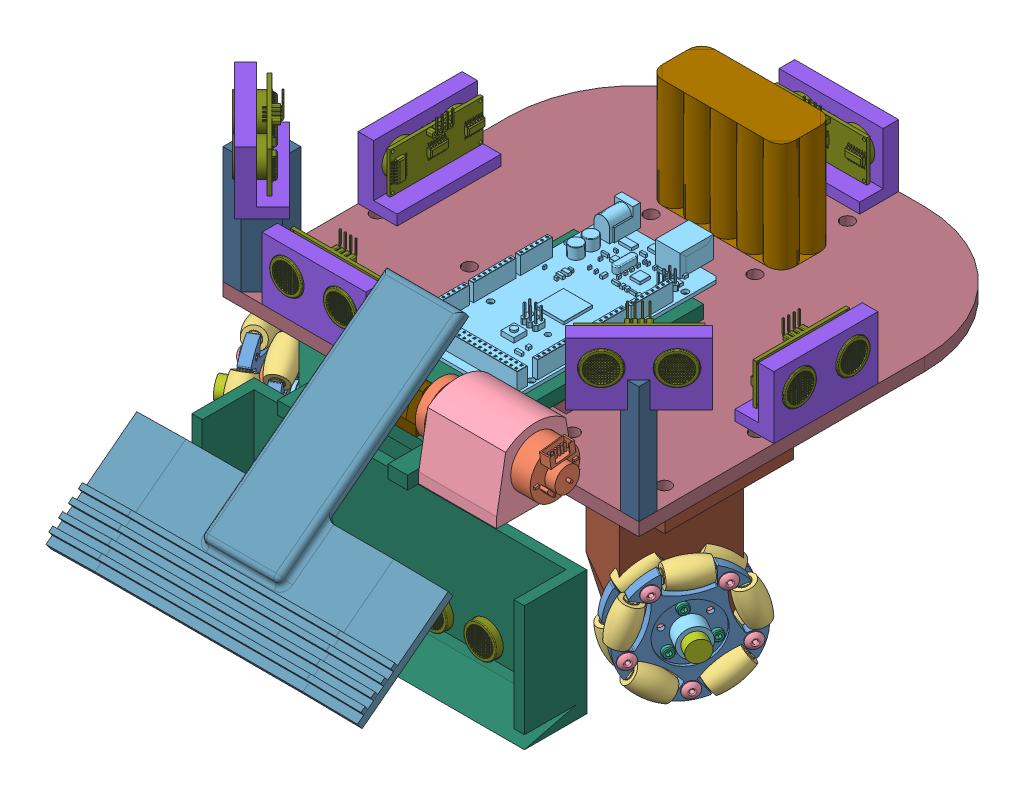
SolidWorks assembly Final_Assem_v3, configuration Default. Lengths in mm.
Overall size (266.21 184.22 334.42).
164 component instances, 32 part files, 108 mates.
Components (placement in the parent):
- WheelAsm-1: WheelAsm [Default] at (158.8212 -186.0529 155.5597) x (-0.148791 -0.954696 0.257713) z (-0.866025 0 -0.5) size (63.86 60.79 27.6)
  - WheelBase-2: WheelBase [Default] at (4.9023 2.731 55.3836) x (1 0 0) z (0 -1 0) size (56.86 5 54.96)
  - BasePlacer-1: BasePlacer [Default] at (4.9023 2.731 58.8836) x (1 0 0) z (0 -1 0) size (28 10 28)
  - RubberWheel-1: RubberWheel [Default] at (4.9023 26.7901 57.8836) x (1 0 0) z (0 -0.999594 -0.028494) size (19 12.5 12.5)
  - RubberWheel-2: RubberWheel [Default] at (-17.9792 10.1657 57.8836) x (0.309017 0.951057 0) z (0.95067 -0.308892 -0.028494) size (19 12.5 12.5)
  - RubberWheel-3: RubberWheel [Default] at (-9.2392 -16.7332 57.8836) x (-0.809017 0.587785 0) z (0.587547 0.808689 -0.028494) size (19 12.5 12.5)
  - RubberWheel-4: RubberWheel [Default] at (19.0439 -16.7332 57.8836) x (-0.809017 -0.587785 0) z (-0.587547 0.808689 -0.028494) size (19 12.5 12.5)
  - RubberWheel-5: RubberWheel [Default] at (27.7839 10.1657 57.8836) x (0.309017 -0.951057 0) z (-0.95067 -0.308892 -0.028494) size (19 12.5 12.5)
  - Rivet-1: Rivet [Default] at (4.9023 -21.269 54.8836) x (1 0 0) z (0 1 0) size (7.46 6.8 7.46)
  - Rivet-2: Rivet [Default] at (27.7277 -4.6854 54.8836) x (0.309017 0.951057 0) z (-0.951057 0.309017 0) size (7.46 6.8 7.46)
  - Rivet-3: Rivet [Default] at (19.0092 22.1474 54.8836) x (-0.809017 0.587785 0) z (-0.587785 -0.809017 0) size (7.46 6.8 7.46)
  - Rivet-4: Rivet [Default] at (-9.2045 22.1474 54.8836) x (-0.809017 -0.587785 0) z (0.587785 -0.809017 0) size (7.46 6.8 7.46)
  - Rivet-5: Rivet [Default] at (-17.923 -4.6854 54.8836) x (0.309017 -0.951057 0) z (0.951057 0.309017 0) size (7.46 6.8 7.46)
  - WheelBase-6: WheelBase [Default] at (4.9023 2.731 67.3836) x (-1 0 0) z (0 1 0) size (56.86 5 54.96)
  - RubberWheel-16: RubberWheel [Default] at (4.9023 -21.3281 69.8836) size (19 12.5 12.5)
  - RubberWheel-17: RubberWheel [Default] at (27.7839 -4.7037 69.8836) x (0.309017 0.951057 0) z (0 0 1) size (19 12.5 12.5)
  - RubberWheel-18: RubberWheel [Default] at (19.0439 22.1953 69.8836) x (-0.809017 0.587785 0) z (0 0 1) size (19 12.5 12.5)
  - RubberWheel-19: RubberWheel [Default] at (-9.2392 22.1953 69.8836) x (-0.809017 -0.587785 0) z (0 0 1) size (19 12.5 12.5)
  - RubberWheel-20: RubberWheel [Default] at (-17.9792 -4.7037 69.8836) x (0.309017 -0.951057 0) z (0 0 1) size (19 12.5 12.5)
  - Rivet-16: Rivet [Default] at (-9.2045 -16.6854 72.8836) x (-0.985624 0.168955 0) z (0.168955 0.985624 0) size (7.46 6.8 7.46)
  - Rivet-17: Rivet [Default] at (19.0092 -16.6854 72.8836) x (-0.46526 -0.885174 0) z (-0.885174 0.46526 0) size (7.46 6.8 7.46)
  - Rivet-18: Rivet [Default] at (27.7277 10.1474 72.8836) x (0.698077 -0.716022 0) z (-0.716022 -0.698077 0) size (7.46 6.8 7.46)
  - Rivet-19: Rivet [Default] at (4.9023 26.731 72.8836) x (0.896695 0.442648 0) z (0.442648 -0.896695 0) size (7.46 6.8 7.46)
  - Rivet-20: Rivet [Default] at (-17.923 10.1474 72.8836) x (-0.143889 0.989594 0) z (0.989594 0.143889 0) size (7.46 6.8 7.46)
  - ShaftConnector-1: ShaftConnector [Default] at (4.9023 2.731 48.8836) x (1 0 0) z (0 -1 0) size (14 27.6 14)
  - Part7^WheelAsm-1: Part7^WheelAsm [Default] at origin (virtual)
  - Part8^WheelAsm-1: Part8^WheelAsm [Default] at origin (virtual)
  - M3HexNut-1: M3HexNut [Default] at (13.9956 7.981 72.8836) x (1 0 0) z (0 0 -1) size (5 5 5)
  - M3HexNut-2: M3HexNut [Default] at (-4.1909 7.981 72.8836) x (-0.5 0.866025 0) z (0 0 -1) size (5 5 5)
  - M3HexNut-3: M3HexNut [Default] at (4.9023 -7.769 72.8836) x (-0.5 -0.866025 0) z (0 0 -1) size (5 5 5)
  - M3HexNut-4: M3HexNut [Default] at (4.9023 -7.769 54.8836) size (5 5 5)
  - M3HexNut-5: M3HexNut [Default] at (13.9956 7.981 54.8836) x (-0.5 0.866025 0) z (0 0 1) size (5 5 5)
  - M3HexNut-6: M3HexNut [Default] at (-4.1909 7.981 54.8836) x (-0.5 -0.866025 0) z (0 0 1) size (5 5 5)
- WheelAsm-2: WheelAsm [Default] at (14.2994 -187.213 -108.2515) x (-0.999988 0.004806 0) z (0 0 1) size (63.86 60.79 27.6)
  - WheelBase-2: WheelBase [Default] at (4.9023 2.731 55.3836) x (1 0 0) z (0 -1 0) size (56.86 5 54.96)
  - BasePlacer-1: BasePlacer [Default] at (4.9023 2.731 58.8836) x (1 0 0) z (0 -1 0) size (28 10 28)
  - RubberWheel-1: RubberWheel [Default] at (4.9023 26.7901 57.8836) x (1 0 0) z (0 -0.999594 -0.028494) size (19 12.5 12.5)
  - RubberWheel-2: RubberWheel [Default] at (-17.9792 10.1657 57.8836) x (0.309017 0.951057 0) z (0.95067 -0.308892 -0.028494) size (19 12.5 12.5)
  - RubberWheel-3: RubberWheel [Default] at (-9.2392 -16.7332 57.8836) x (-0.809017 0.587785 0) z (0.587547 0.808689 -0.028494) size (19 12.5 12.5)
  - RubberWheel-4: RubberWheel [Default] at (19.0439 -16.7332 57.8836) x (-0.809017 -0.587785 0) z (-0.587547 0.808689 -0.028494) size (19 12.5 12.5)
  - RubberWheel-5: RubberWheel [Default] at (27.7839 10.1657 57.8836) x (0.309017 -0.951057 0) z (-0.95067 -0.308892 -0.028494) size (19 12.5 12.5)
  - Rivet-1: Rivet [Default] at (4.9023 -21.269 54.8836) x (1 0 0) z (0 1 0) size (7.46 6.8 7.46)
  - Rivet-2: Rivet [Default] at (27.7277 -4.6854 54.8836) x (0.309017 0.951057 0) z (-0.951057 0.309017 0) size (7.46 6.8 7.46)
  - Rivet-3: Rivet [Default] at (19.0092 22.1474 54.8836) x (-0.809017 0.587785 0) z (-0.587785 -0.809017 0) size (7.46 6.8 7.46)
  - Rivet-4: Rivet [Default] at (-9.2045 22.1474 54.8836) x (-0.809017 -0.587785 0) z (0.587785 -0.809017 0) size (7.46 6.8 7.46)
  - Rivet-5: Rivet [Default] at (-17.923 -4.6854 54.8836) x (0.309017 -0.951057 0) z (0.951057 0.309017 0) size (7.46 6.8 7.46)
  - WheelBase-6: WheelBase [Default] at (4.9023 2.731 67.3836) x (-1 0 0) z (0 1 0) size (56.86 5 54.96)
  - RubberWheel-16: RubberWheel [Default] at (4.9023 -21.3281 69.8836) size (19 12.5 12.5)
  - RubberWheel-17: RubberWheel [Default] at (27.7839 -4.7037 69.8836) x (0.309017 0.951057 0) z (0 0 1) size (19 12.5 12.5)
  - RubberWheel-18: RubberWheel [Default] at (19.0439 22.1953 69.8836) x (-0.809017 0.587785 0) z (0 0 1) size (19 12.5 12.5)
  - RubberWheel-19: RubberWheel [Default] at (-9.2392 22.1953 69.8836) x (-0.809017 -0.587785 0) z (0 0 1) size (19 12.5 12.5)
  - RubberWheel-20: RubberWheel [Default] at (-17.9792 -4.7037 69.8836) x (0.309017 -0.951057 0) z (0 0 1) size (19 12.5 12.5)
  - Rivet-16: Rivet [Default] at (-9.2045 -16.6854 72.8836) x (-0.985624 0.168955 0) z (0.168955 0.985624 0) size (7.46 6.8 7.46)
  - Rivet-17: Rivet [Default] at (19.0092 -16.6854 72.8836) x (-0.46526 -0.885174 0) z (-0.885174 0.46526 0) size (7.46 6.8 7.46)
  - Rivet-18: Rivet [Default] at (27.7277 10.1474 72.8836) x (0.698077 -0.716022 0) z (-0.716022 -0.698077 0) size (7.46 6.8 7.46)
  - Rivet-19: Rivet [Default] at (4.9023 26.731 72.8836) x (0.896695 0.442648 0) z (0.442648 -0.896695 0) size (7.46 6.8 7.46)
  - Rivet-20: Rivet [Default] at (-17.923 10.1474 72.8836) x (-0.143889 0.989594 0) z (0.989594 0.143889 0) size (7.46 6.8 7.46)
  - ShaftConnector-1: ShaftConnector [Default] at (4.9023 2.731 48.8836) x (1 0 0) z (0 -1 0) size (14 27.6 14)
  - Part7^WheelAsm-1: Part7^WheelAsm [Default] at origin (virtual)
  - Part8^WheelAsm-1: Part8^WheelAsm [Default] at origin (virtual)
  - M3HexNut-1: M3HexNut [Default] at (13.9956 7.981 72.8836) x (1 0 0) z (0 0 -1) size (5 5 5)
  - M3HexNut-2: M3HexNut [Default] at (-4.1909 7.981 72.8836) x (-0.5 0.866025 0) z (0 0 -1) size (5 5 5)
  - M3HexNut-3: M3HexNut [Default] at (4.9023 -7.769 72.8836) x (-0.5 -0.866025 0) z (0 0 -1) size (5 5 5)
  - M3HexNut-4: M3HexNut [Default] at (4.9023 -7.769 54.8836) size (5 5 5)
  - M3HexNut-5: M3HexNut [Default] at (13.9956 7.981 54.8836) x (-0.5 0.866025 0) z (0 0 1) size (5 5 5)
  - M3HexNut-6: M3HexNut [Default] at (-4.1909 7.981 54.8836) x (-0.5 -0.866025 0) z (0 0 1) size (5 5 5)
- WheelAsm-3: WheelAsm [Default] at (-151.0302 -191.8955 160.5271) x (0.323209 0.762983 0.559814) z (0.866025 0 -0.5) size (63.86 60.79 27.6)
  - WheelBase-2: WheelBase [Default] at (4.9023 2.731 55.3836) x (1 0 0) z (0 -1 0) size (56.86 5 54.96)
  - BasePlacer-1: BasePlacer [Default] at (4.9023 2.731 58.8836) x (1 0 0) z (0 -1 0) size (28 10 28)
  - RubberWheel-1: RubberWheel [Default] at (4.9023 26.7901 57.8836) x (1 0 0) z (0 -0.999594 -0.028494) size (19 12.5 12.5)
  - RubberWheel-2: RubberWheel [Default] at (-17.9792 10.1657 57.8836) x (0.309017 0.951057 0) z (0.95067 -0.308892 -0.028494) size (19 12.5 12.5)
  - RubberWheel-3: RubberWheel [Default] at (-9.2392 -16.7332 57.8836) x (-0.809017 0.587785 0) z (0.587547 0.808689 -0.028494) size (19 12.5 12.5)
  - RubberWheel-4: RubberWheel [Default] at (19.0439 -16.7332 57.8836) x (-0.809017 -0.587785 0) z (-0.587547 0.808689 -0.028494) size (19 12.5 12.5)
  - RubberWheel-5: RubberWheel [Default] at (27.7839 10.1657 57.8836) x (0.309017 -0.951057 0) z (-0.95067 -0.308892 -0.028494) size (19 12.5 12.5)
  - Rivet-1: Rivet [Default] at (4.9023 -21.269 54.8836) x (1 0 0) z (0 1 0) size (7.46 6.8 7.46)
  - Rivet-2: Rivet [Default] at (27.7277 -4.6854 54.8836) x (0.309017 0.951057 0) z (-0.951057 0.309017 0) size (7.46 6.8 7.46)
  - Rivet-3: Rivet [Default] at (19.0092 22.1474 54.8836) x (-0.809017 0.587785 0) z (-0.587785 -0.809017 0) size (7.46 6.8 7.46)
  - Rivet-4: Rivet [Default] at (-9.2045 22.1474 54.8836) x (-0.809017 -0.587785 0) z (0.587785 -0.809017 0) size (7.46 6.8 7.46)
  - Rivet-5: Rivet [Default] at (-17.923 -4.6854 54.8836) x (0.309017 -0.951057 0) z (0.951057 0.309017 0) size (7.46 6.8 7.46)
  - WheelBase-6: WheelBase [Default] at (4.9023 2.731 67.3836) x (-1 0 0) z (0 1 0) size (56.86 5 54.96)
  - RubberWheel-16: RubberWheel [Default] at (4.9023 -21.3281 69.8836) size (19 12.5 12.5)
  - RubberWheel-17: RubberWheel [Default] at (27.7839 -4.7037 69.8836) x (0.309017 0.951057 0) z (0 0 1) size (19 12.5 12.5)
  - RubberWheel-18: RubberWheel [Default] at (19.0439 22.1953 69.8836) x (-0.809017 0.587785 0) z (0 0 1) size (19 12.5 12.5)
  - RubberWheel-19: RubberWheel [Default] at (-9.2392 22.1953 69.8836) x (-0.809017 -0.587785 0) z (0 0 1) size (19 12.5 12.5)
  - RubberWheel-20: RubberWheel [Default] at (-17.9792 -4.7037 69.8836) x (0.309017 -0.951057 0) z (0 0 1) size (19 12.5 12.5)
  - Rivet-16: Rivet [Default] at (-9.2045 -16.6854 72.8836) x (-0.985624 0.168955 0) z (0.168955 0.985624 0) size (7.46 6.8 7.46)
  - Rivet-17: Rivet [Default] at (19.0092 -16.6854 72.8836) x (-0.46526 -0.885174 0) z (-0.885174 0.46526 0) size (7.46 6.8 7.46)
  - Rivet-18: Rivet [Default] at (27.7277 10.1474 72.8836) x (0.698077 -0.716022 0) z (-0.716022 -0.698077 0) size (7.46 6.8 7.46)
  - Rivet-19: Rivet [Default] at (4.9023 26.731 72.8836) x (0.896695 0.442648 0) z (0.442648 -0.896695 0) size (7.46 6.8 7.46)
  - Rivet-20: Rivet [Default] at (-17.923 10.1474 72.8836) x (-0.143889 0.989594 0) z (0.989594 0.143889 0) size (7.46 6.8 7.46)
  - ShaftConnector-1: ShaftConnector [Default] at (4.9023 2.731 48.8836) x (1 0 0) z (0 -1 0) size (14 27.6 14)
  - Part7^WheelAsm-1: Part7^WheelAsm [Default] at origin (virtual)
  - Part8^WheelAsm-1: Part8^WheelAsm [Default] at origin (virtual)
  - M3HexNut-1: M3HexNut [Default] at (13.9956 7.981 72.8836) x (1 0 0) z (0 0 -1) size (5 5 5)
  - M3HexNut-2: M3HexNut [Default] at (-4.1909 7.981 72.8836) x (-0.5 0.866025 0) z (0 0 -1) size (5 5 5)
  - M3HexNut-3: M3HexNut [Default] at (4.9023 -7.769 72.8836) x (-0.5 -0.866025 0) z (0 0 -1) size (5 5 5)
  - M3HexNut-4: M3HexNut [Default] at (4.9023 -7.769 54.8836) size (5 5 5)
  - M3HexNut-5: M3HexNut [Default] at (13.9956 7.981 54.8836) x (-0.5 0.866025 0) z (0 0 1) size (5 5 5)
  - M3HexNut-6: M3HexNut [Default] at (-4.1909 7.981 54.8836) x (-0.5 -0.866025 0) z (0 0 1) size (5 5 5)
- DC Motor 12V-1: DC Motor 12V [Predeterminado] at (-59.1254 -189.9205 113.5312) x (0.5 0 0.866025) z (-0.866025 0 0.5) size (28.03 28 53.5)
  - Carcaça12V-1: Carcaça12V [Predeterminado] at (0 0 24.0663) size (28.03 28 32.04)
  - Bucha12V-1: Bucha12V [Predeterminado] at (0 0 26.0163) x (0.994754 0.102295 0) z (0 0 1) size (7 7 0.5)
  - Mancal12V-1: Mancal12V [Predeterminado] at (0 0 -2.9337) x (-1 0 0) z (0 0 -1) size (27.69 28 8)
  - Terminal12V-1: Terminal12V [Predeterminado] at (0 -11.5 -3.9337) x (1 0 0) z (0 1 0) size (2.9 10 0.4)
  - Terminal12V-2: Terminal12V [Predeterminado] at (0 11.5 -3.9337) x (1 0 0) z (0 1 0) size (2.9 10 0.4)
  - Eixo12V-1: Eixo12V [Predeterminado] at (0 0 39.5663) x (-0.33009 -0.943949 0) z (0 0 1) size (21 20.89 51)
  - Enrolamento12V-1: Enrolamento12V [Predeterminado] at (-5.1702 1.808 12.5663) x (0.33009 0.943949 0) z (0 0 1) size (10 3 20)
  - Enrolamento12V-2: Enrolamento12V [Predeterminado] at (1.0194 -5.3815 12.5663) x (-0.982529 -0.186108 0) z (0 0 1) size (10 3 20)
  - Enrolamento12V-3: Enrolamento12V [Predeterminado] at (4.1509 3.5736 12.5663) x (0.652439 -0.757841 0) z (0 0 1) size (10 3 20)
- DC Motor 12V-2: DC Motor 12V [Predeterminado] at (67.5444 -189.9205 107.5562) x (-0.212518 0.905176 0.368092) z (0.866025 0 0.5) size (28.03 28 53.5)
  - Carcaça12V-1: Carcaça12V [Predeterminado] at (0 0 24.0663) size (28.03 28 32.04)
  - Bucha12V-1: Bucha12V [Predeterminado] at (0 0 26.0163) x (0.994754 0.102295 0) z (0 0 1) size (7 7 0.5)
  - Mancal12V-1: Mancal12V [Predeterminado] at (0 0 -2.9337) x (-1 0 0) z (0 0 -1) size (27.69 28 8)
  - Terminal12V-1: Terminal12V [Predeterminado] at (0 -11.5 -3.9337) x (1 0 0) z (0 1 0) size (2.9 10 0.4)
  - Terminal12V-2: Terminal12V [Predeterminado] at (0 11.5 -3.9337) x (1 0 0) z (0 1 0) size (2.9 10 0.4)
  - Eixo12V-1: Eixo12V [Predeterminado] at (0 0 39.5663) x (-0.33009 -0.943949 0) z (0 0 1) size (21 20.89 51)
  - Enrolamento12V-1: Enrolamento12V [Predeterminado] at (-5.1702 1.808 12.5663) x (0.33009 0.943949 0) z (0 0 1) size (10 3 20)
  - Enrolamento12V-2: Enrolamento12V [Predeterminado] at (1.0194 -5.3815 12.5663) x (-0.982529 -0.186108 0) z (0 0 1) size (10 3 20)
  - Enrolamento12V-3: Enrolamento12V [Predeterminado] at (4.1509 3.5736 12.5663) x (0.652439 -0.757841 0) z (0 0 1) size (10 3 20)
- Acrylic Plate (square 12 inch) cut version-1: Acrylic Plate (square 12 inch) cut version [Default] at (9.384 -134.5485 57.0478) size (203.2 6.35 203.2)
- ScoopClawAssembly-1: ScoopClawAssembly [Default] at (-135.2234 -155.5644 109.464) size (171.3 138.74 218)
  - Scooper-1: Scooper [Default] at (144.6073 0.6103 138.0053) x (1 0 0) z (0 0.793599 0.608442) size (152.65 142.24 11.1)
  - Scooper_Base-1: Scooper_Base [Default] at (144.6073 -61.534 72.0438) size (162.56 95.25 144.78)
  - HC-SR04-UltrasonicSensor v7-2: HC-SR04-UltrasonicSensor v7 [Default] at (144.5683 -48.834 48.9638) x (-1 0 0) z (0 0 1) size (45.45 26.2 17.79)
  - Hinge_Joint-1: Hinge_Joint [Default] at (126.8273 46.416 67.8239) x (0 0.774266 0.63286) z (1 0 0) size (8.89 8.89 40.64)
  - Hinge_Part1-1: Hinge_Part1 [Default] at (144.6073 33.716 67.8239) size (35.56 18.62 12.7)
  - Hinge_Part2-1: Hinge_Part2 [Default] at (144.6073 54.4789 74.0056) x (1 0 0) z (0 0.608442 -0.793599) size (25.4 16.08 12.7)
  - 6V Motor Spin-1: 6V Motor Spin [Default] at (231.6559 14.0419 25.1949) x (-0.072098 -0.103157 0.992049) z (-0.996718 0.044149 -0.067847) size (29.63 28.32 78.39)
    - Motor no spinny boi-1: Motor no spinny boi [Default] at (39.6165 36.3483 7.7453) x (0.997226 -0.015871 -0.072721) z (0.072098 -0.036799 0.996718) size (24.4 25.49 66.9)
    - Motor spinny boi-1: Motor spinny boi [Default] at (39.6165 36.3483 7.7453) x (0.547957 0.836461 -0.008754) z (0.072098 -0.036799 0.996718) size (3.95 3.95 13.05)
  - Motor Support-1: Motor Support [Default] at (195.4073 27.366 67.8239) size (38.1 54.53 38.1)
- ArduinoMega-1: ArduinoMega [Default] at (9.3459 -119.6895 95.1478) x (0 0 -1) z (0 -1 0) size (107.95 53.42 12.95)
- 12V Motor Support -Right-2: 12V Motor Support -Right [Default] at (-60.72 -189.9205 114.4518) x (0.866025 0 -0.5) z (0.5 0 0.866025) size (86.05 76.69 86.05)
- OmniWheel_Connection Piece-2: OmniWheel_Connection Piece [Default] at (90.257 -189.9205 120.6693) x (-0.490726 0.19171 0.849962) z (0.866025 0 0.5) size (10.16 10.16 33.02)
- OmniWheel_Connection Piece-3: OmniWheel_Connection Piece [Default] at (-81.8727 -189.9205 126.6643) x (0.5 0 0.866025) z (-0.866025 0 0.5) size (10.16 10.16 33.02)
- HC-SR04-UltrasonicSensor v7-1: HC-SR04-UltrasonicSensor v7 [Default] at (-40.996 -204.3985 158.4278) x (-1 0 0) z (0 0 1) size (45.45 26.2 17.79)
- HC-SR04-UltrasonicSensor v7-2: HC-SR04-UltrasonicSensor v7 [Default] at (59.764 -204.3985 158.4278) x (-1 0 0) z (0 0 1) size (45.45 26.2 17.79)
- US_Support-2: US_Support [Default] at (103.364 -123.1185 67.2078) x (0 0 -1) z (1 0 0) size (50.8 30.48 19.05)
- US_Support-3: US_Support [Default] at (-84.596 -123.1185 67.2078) x (0 0 1) z (-1 0 0) size (50.8 30.48 19.05)
- BatteryRemodeled-2: BatteryRemodeled [Default] at (34.784 -76.1031 -0.1022) x (-1 0 0) z (0 0 1) size (64.52 53.39 25.65)
- US_Support-4: US_Support [Default] at (9.384 -123.1185 -36.9322) x (-1 0 0) z (0 0 -1) size (50.8 30.48 19.05)
- US_Support-5: US_Support [Default] at (-47.766 -123.1185 151.0278) size (50.8 30.48 19.05)
- HC-SR04-UltrasonicSensor v7-3: HC-SR04-UltrasonicSensor v7 [Default] at (98.064 -110.4185 67.1688) x (0 0 1) z (1 0 0) size (45.45 26.2 17.79)
- HC-SR04-UltrasonicSensor v7-4: HC-SR04-UltrasonicSensor v7 [Default] at (9.345 -110.4185 -31.6322) x (1 0 0) z (0 0 -1) size (45.45 26.2 17.79)
- HC-SR04-UltrasonicSensor v7-5: HC-SR04-UltrasonicSensor v7 [Default] at (-79.296 -110.4185 67.1688) x (0 0 -1) z (-1 0 0) size (45.45 26.2 17.79)
- corner_support-1: corner_support [Default] at (-82.691 -128.1985 149.1228) size (19.05 57.15 19.05)
- US_Support-6: US_Support [Default] at (-84.1338 -78.6685 150.386) x (0.707107 0 0.707107) z (-0.707107 0 0.707107) size (50.8 30.48 19.05)
- HC-SR04-UltrasonicSensor v7-6: HC-SR04-UltrasonicSensor v7 [Default] at (-80.3586 -65.9685 146.6659) x (-0.707107 0 -0.707107) z (-0.707107 0 0.707107) size (45.45 26.2 17.79)
- HC-SR04-UltrasonicSensor v7-7: HC-SR04-UltrasonicSensor v7 [Default] at (-47.805 -110.4185 145.7278) x (-1 0 0) z (0 0 1) size (45.45 26.2 17.79)
- corner_support-2: corner_support [Default] at (101.459 -128.1985 149.1228) x (0 0 -1) z (1 0 0) size (19.05 57.15 19.05)
- US_Support-7: US_Support [Default] at (102.9017 -78.6685 150.386) x (0.707107 0 -0.707107) z (0.707107 0 0.707107) size (50.8 30.48 19.05)
- HC-SR04-UltrasonicSensor v7-8: HC-SR04-UltrasonicSensor v7 [Default] at (99.1265 -65.9685 146.6659) x (-0.707107 0 0.707107) z (0.707107 0 0.707107) size (45.45 26.2 17.79)
- 12V Motor Support - Left-1: 12V Motor Support - Left [Default] at (79.488 -189.9205 114.4518) x (0.866025 0 0.5) z (-0.5 0 0.866025) size (86.05 76.69 86.05)
- DC Motor 12V-3: DC Motor 12V [Predeterminado] at (9.384 -189.9205 -5.2016) x (-0.923728 -0.383049 0) z (0 0 -1) size (28.03 28 53.5)
  - Carcaça12V-1: Carcaça12V [Predeterminado] at (0 0 24.0663) size (28.03 28 32.04)
  - Bucha12V-1: Bucha12V [Predeterminado] at (0 0 26.0163) x (0.994754 0.102295 0) z (0 0 1) size (7 7 0.5)
  - Mancal12V-1: Mancal12V [Predeterminado] at (0 0 -2.9337) x (-1 0 0) z (0 0 -1) size (27.69 28 8)
  - Terminal12V-1: Terminal12V [Predeterminado] at (0 -11.5 -3.9337) x (1 0 0) z (0 1 0) size (2.9 10 0.4)
  - Terminal12V-2: Terminal12V [Predeterminado] at (0 11.5 -3.9337) x (1 0 0) z (0 1 0) size (2.9 10 0.4)
  - Eixo12V-1: Eixo12V [Predeterminado] at (0 0 39.5663) x (-0.33009 -0.943949 0) z (0 0 1) size (21 20.89 51)
  - Enrolamento12V-1: Enrolamento12V [Predeterminado] at (-5.1702 1.808 12.5663) x (0.33009 0.943949 0) z (0 0 1) size (10 3 20)
  - Enrolamento12V-2: Enrolamento12V [Predeterminado] at (1.0194 -5.3815 12.5663) x (-0.982529 -0.186108 0) z (0 0 1) size (10 3 20)
  - Enrolamento12V-3: Enrolamento12V [Predeterminado] at (4.1509 3.5736 12.5663) x (0.652439 -0.757841 0) z (0 0 1) size (10 3 20)
- 12V Motor Support - Rear-1: 12V Motor Support - Rear [Default] at (9.384 -189.9205 -7.0429) x (0 0 -1) z (1 0 0) size (62.99 76.31 63.5)
Mates (geometry in assembly coordinates):
- Coincident3: coincident: plane of Acrylic Plate (square 12 inch) cut version-1 through (9.384 -128.1985 57.0478) normal (0 1 0); plane of ScoopClawAssembly-1/Scooper_Base-1 through (9.384 -128.1985 181.5078) normal (0 -1 0)
- Coincident4: coincident: plane of Acrylic Plate (square 12 inch) cut version-1 through (-92.216 -128.1985 158.6478) normal (0 0 1); plane of ScoopClawAssembly-1/Scooper_Base-1 through (9.384 -217.0985 158.6478) normal (0 0 -1)
- Distance4: distance = 0.508 mm: plane of ScoopClawAssembly-1/Scooper_Base-1 through (9.384 -121.8485 181.5078) normal (0 1 0); plane of ArduinoMega-1 through (-17.3622 -121.3405 44.3478) normal (0 -1 0)
- Distance6: distance = 12.7 mm: plane of ArduinoMega-1 through (36.054 -121.3405 44.3478) normal (0 0 -1); plane of ScoopClawAssembly-1/Scooper_Base-1 through (41.134 -121.8485 57.0478) normal (0 0 -1)
- Distance7: distance = 5.08 mm: plane of ArduinoMega-1 through (36.054 -121.3405 145.9478) normal (1 0 0); plane of ScoopClawAssembly-1/Scooper_Base-1 through (41.134 -166.2985 158.6478) normal (1 0 0)
- Coincident23: coincident: plane of Acrylic Plate (square 12 inch) cut version-1 through (9.384 -134.5485 57.0478) normal (0 -1 0); plane of ? through (146.5657 -134.5485 103.1381) normal (0 1 0)
- Coincident29: coincident: plane of Acrylic Plate (square 12 inch) cut version-1 through (9.384 -134.5485 57.0478) normal (0 -1 0); plane of 12V Motor Support -Right-2 through (-60.72 -134.5485 114.4518) normal (0 1 0)
- Concentric1: concentric: cylinder of DC Motor 12V-1/Carcaça12V-1 through (-54.8527 -189.9205 111.0643) axis (-0.866025 0 0.5) radius 14; cylinder of 12V Motor Support -Right-2 through (-151.4579 -189.9205 166.8393) axis (0.866025 0 -0.5) radius 17.145
- Coincident31: coincident: plane of DC Motor 12V-1/Carcaça12V-1 through (-79.9675 -189.9205 125.5643) normal (-0.866025 0 0.5); plane of 12V Motor Support -Right-2 through (-68.855 -139.6285 144.8117) normal (-0.866025 0 0.5)
- Coincident32: coincident: plane of DC Motor 12V-2/Carcaça12V-1; plane of ? through (144.59 -139.6285 128.1032) normal (0.707107 0 0.707107)
- Concentric2: concentric: cylinder of DC Motor 12V-2/Carcaça12V-1 through (137.5543 -189.9205 94.1267) axis (0.707107 0 0.707107) radius 14; cylinder of ? through (68.2578 -189.9205 24.8302) axis (0.707107 0 0.707107) radius 13.9872
- Concentric4: concentric: circle of WheelAsm-1/ShaftConnector-1; circle of DC Motor 12V-2/Eixo12V-1
- Coincident36: coincident: plane of WheelAsm-1/ShaftConnector-1 through (90.5514 -189.9205 120.8393) normal (-0.866025 0 -0.5); plane of DC Motor 12V-2/Carcaça12V-1 through (90.5514 -189.9205 120.8393) normal (0.866025 0 0.5)
- Concentric8: concentric: circle of WheelAsm-1/ShaftConnector-1; circle of OmniWheel_Connection Piece-2
- Coincident39: coincident: plane of WheelAsm-1/ShaftConnector-1 through (114.4537 -189.9205 134.6393) normal (0.866025 0 0.5); plane of OmniWheel_Connection Piece-2 through (114.4537 -189.9205 134.6393) normal (-0.866025 0 -0.5)
- Distance9: distance = 69.85 mm: plane of ScoopClawAssembly-1/Scooper_Base-1 through (-22.366 -128.1985 158.6478) normal (-1 0 0); plane of Acrylic Plate (square 12 inch) cut version-1 through (-92.216 -128.1985 158.6478) normal (-1 0 0)
- Concentric9: concentric: circle of WheelAsm-3/ShaftConnector-1; circle of DC Motor 12V-1/Eixo12V-1
- Coincident42: coincident: plane of WheelAsm-3/ShaftConnector-1 through (-106.0695 -189.9205 140.6343) normal (-0.866025 0 0.5); plane of OmniWheel_Connection Piece-3 through (-106.0695 -189.9205 140.6343) normal (0.866025 0 -0.5)
- Concentric10: concentric: circle of WheelAsm-3/ShaftConnector-1; circle of OmniWheel_Connection Piece-3
- Coincident43: coincident: plane of DC Motor 12V-1/Bucha12V-1 through (-81.8727 -189.9205 126.6643) normal (-0.866025 0 0.5); plane of OmniWheel_Connection Piece-3 through (-81.8727 -189.9205 126.6643) normal (0.866025 0 -0.5)
- Coincident45: coincident: plane of Acrylic Plate (square 12 inch) cut version-1 through (9.384 -134.5485 57.0478) normal (0 -1 0); plane of ? through (9.384 -134.5485 2.4378) normal (0 1 0)
- Concentric13: concentric: circle of WheelAsm-2/ShaftConnector-1; circle of ?
- Concentric14: concentric: circle of WheelAsm-2/ShaftConnector-1; circle of ?
- Coincident52: coincident: plane of WheelAsm-2/ShaftConnector-1 through (9.384 -189.9205 -53.3622) normal (0 0 -1); plane of ? through (9.384 -189.9205 -53.3622) normal (0 0 1)
- Distance13: distance = 18.034 mm: plane of ? through (41.134 -134.5485 -26.5182) normal (0 0 -1); plane of Acrylic Plate (square 12 inch) cut version-1 through (-92.216 -128.1985 -44.5522) normal (0 0 -1)
- Distance15: distance = 69.85 mm: plane of ? through (41.134 -134.5485 -26.5182) normal (1 0 0); plane of Acrylic Plate (square 12 inch) cut version-1 through (110.984 -128.1985 158.6478) normal (1 0 0)
- Coincident73: coincident: plane of ScoopClawAssembly-1/Scooper_Base-1 through (9.384 -121.8485 181.5078) normal (0 1 0); plane of ? through (38.594 -121.8485 59.5878) normal (0 -1 0)
- Coincident74: coincident: plane of ScoopClawAssembly-1/Scooper_Base-1 through (41.134 -121.8485 57.0478) normal (0 0 -1); plane of ? through (41.134 -121.8485 57.0478) normal (0 0 -1)
- Coincident75: coincident: plane of ScoopClawAssembly-1/Scooper_Base-1 through (41.134 -166.2985 158.6478) normal (1 0 0); plane of ? through (41.134 -121.8485 62.1278) normal (1 0 0)
- Coincident76: coincident: plane of ScoopClawAssembly-1/Scooper_Base-1 through (41.134 -121.8485 57.0478) normal (0 0 -1); plane of ? through (-22.366 -83.7485 57.0478) normal (0 0 -1)
- Coincident77: coincident: plane of ScoopClawAssembly-1/Scooper_Base-1 through (9.384 -121.8485 181.5078) normal (0 1 0); plane of ? through (-19.826 -121.8485 59.5878) normal (0 -1 0)
- Coincident78: coincident: plane of ScoopClawAssembly-1/Scooper_Base-1 through (-22.366 -128.1985 158.6478) normal (-1 0 0); plane of ? through (-22.366 -83.7485 62.1278) normal (-1 0 0)
- Coincident79: coincident: plane of ScoopClawAssembly-1/Scooper_Base-1 through (9.384 -121.8485 181.5078) normal (0 1 0); plane of ? through (38.594 -121.8485 105.3042) normal (0 -1 0)
- Coincident80: coincident: plane of ? through (41.134 -121.8485 62.1278) normal (1 0 0); plane of ? through (41.134 -121.8485 107.8442) normal (1 0 0)
- Distance21: distance = 55.4736 mm: plane of ? through (41.134 -121.8485 102.7642) normal (0 0 -1); plane of ScoopClawAssembly-1/Motor Support-1 through (41.134 -123.1185 158.2378) normal (0 0 -1)
- Coincident82: coincident: plane of ? through (-22.366 -83.7485 102.7642) normal (0 0 -1); plane of ? through (41.134 -121.8485 102.7642) normal (0 0 -1)
- Coincident83: coincident: plane of ScoopClawAssembly-1/Scooper_Base-1 through (9.384 -121.8485 181.5078) normal (0 1 0); plane of ? through (-19.826 -121.8485 105.3042) normal (0 -1 0)
- Coincident84: coincident: plane of ScoopClawAssembly-1/Scooper_Base-1 through (-22.366 -128.1985 158.6478) normal (-1 0 0); plane of ? through (-22.366 -83.7485 107.8442) normal (-1 0 0)
- Coincident85: coincident: plane of ? through (38.594 -83.7485 59.5878) normal (0 1 0); plane of ? through (9.384 -83.7485 82.4478) normal (0 -1 0)
- Coincident88: coincident: plane of ? through (-22.366 -83.7485 57.0478) normal (0 0 -1); plane of ? through (60.184 -77.3985 57.0478) normal (0 0 -1)
- Distance22: distance = 19.05 mm: plane of ? through (-41.416 -77.3985 57.0478) normal (-1 0 0); plane of ? through (-22.366 -83.7485 62.1278) normal (-1 0 0)
- Coincident91: coincident: plane of ScoopClawAssembly-1/Scooper_Base-1 through (9.384 -217.0985 163.7278) normal (0 0 -1); plane of HC-SR04-UltrasonicSensor v7-2 through (59.764 -211.7841 163.7278) normal (0 0 1)
- Parallel9: parallel: plane of ScoopClawAssembly-1/Scooper_Base-1 through (9.384 -217.0985 181.5078) normal (0 -1 0); plane of HC-SR04-UltrasonicSensor v7-2 through (37.039 -214.3985 158.4278) normal (0 -1 0)
- Parallel10: parallel: plane of ScoopClawAssembly-1/Scooper_Base-1 through (9.384 -217.0985 181.5078) normal (0 -1 0); plane of HC-SR04-UltrasonicSensor v7-1 through (-63.721 -214.3985 158.4278) normal (0 -1 0)
- Coincident94: coincident: plane of ScoopClawAssembly-1/Scooper_Base-1 through (9.384 -217.0985 163.7278) normal (0 0 -1); plane of HC-SR04-UltrasonicSensor v7-1 through (-40.996 -211.7841 163.7278) normal (0 0 1)
- Coincident95: coincident: plane of Acrylic Plate (square 12 inch) cut version-1 through (110.984 -128.1985 158.6478) normal (1 0 0); plane of US_Support-2 through (110.984 -123.1185 67.2078) normal (1 0 0)
- Coincident96: coincident: plane of Acrylic Plate (square 12 inch) cut version-1 through (9.384 -128.1985 57.0478) normal (0 1 0); plane of US_Support-2 through (103.364 -128.1985 67.2078) normal (0 -1 0)
- Distance23: distance = 86.36 mm: plane of US_Support-2 through (110.984 -123.1185 41.8078) normal (0 0 -1); plane of Acrylic Plate (square 12 inch) cut version-1 through (-92.216 -128.1985 -44.5522) normal (0 0 -1)
- Coincident98: coincident: plane of US_Support-2 through (110.984 -123.1185 92.6078) normal (0 0 1); plane of US_Support-3 through (-92.216 -123.1185 92.6078) normal (0 0 1)
- Coincident99: coincident: plane of Acrylic Plate (square 12 inch) cut version-1 through (9.384 -128.1985 57.0478) normal (0 1 0); plane of US_Support-3 through (-84.596 -128.1985 67.2078) normal (0 -1 0)
- Coincident100: coincident: plane of Acrylic Plate (square 12 inch) cut version-1 through (-92.216 -128.1985 158.6478) normal (-1 0 0); plane of US_Support-3 through (-92.216 -123.1185 67.2078) normal (-1 0 0)
- Coincident101: coincident: plane of Acrylic Plate (square 12 inch) cut version-1 through (9.384 -128.1985 57.0478) normal (0 1 0); plane of BatteryRemodeled-2 through (34.784 -128.1985 -0.1022) normal (0 -1 0)
- Distance24: distance = 38.1 mm: line of BatteryRemodeled-2 through (-4.078 -128.1731 -6.4522) axis (1 0 0); line of Acrylic Plate (square 12 inch) cut version-1 through (47.484 -128.1985 -44.5522) axis (-1 0 0)
- Distance25: distance = 69.85 mm: line of BatteryRemodeled-2 through (41.134 -128.1731 -0.1022) axis (0 0 1); line of Acrylic Plate (square 12 inch) cut version-1 through (110.984 -128.1985 158.6478) axis (0 0 -1)
- Coincident106: coincident: plane of Acrylic Plate (square 12 inch) cut version-1 through (-92.216 -128.1985 -44.5522) normal (0 0 -1); plane of US_Support-4 through (9.384 -123.1185 -44.5522) normal (0 0 -1)
- Coincident107: coincident: plane of Acrylic Plate (square 12 inch) cut version-1 through (9.384 -128.1985 57.0478) normal (0 1 0); plane of US_Support-4 through (9.384 -128.1985 -36.9322) normal (0 -1 0)
- Distance26: distance = 76.2 mm: plane of US_Support-4 through (-16.016 -123.1185 -44.5522) normal (-1 0 0); plane of Acrylic Plate (square 12 inch) cut version-1 through (-92.216 -128.1985 158.6478) normal (-1 0 0)
- Coincident109: coincident: plane of Acrylic Plate (square 12 inch) cut version-1 through (9.384 -128.1985 57.0478) normal (0 1 0); plane of US_Support-5 through (-47.766 -128.1985 151.0278) normal (0 -1 0)
- Distance27: distance = 19.05 mm: plane of US_Support-5 through (-73.166 -123.1185 158.6478) normal (-1 0 0); plane of Acrylic Plate (square 12 inch) cut version-1 through (-92.216 -128.1985 158.6478) normal (-1 0 0)
- Coincident111: coincident: plane of Acrylic Plate (square 12 inch) cut version-1 through (-92.216 -128.1985 158.6478) normal (0 0 1); plane of US_Support-5 through (-47.766 -123.1185 158.6478) normal (0 0 1)
- Concentric20: concentric: cylinder of HC-SR04-UltrasonicSensor v7-5 through (-80.896 -110.4185 80.2888) axis (-1 0 0) radius 8; cylinder of US_Support-3 through (-92.216 -110.4185 80.2888) axis (1 0 0) radius 8.2697
- Parallel16: parallel: plane of US_Support-3 through (-92.216 -97.7185 41.8078) normal (0 1 0); plane of HC-SR04-UltrasonicSensor v7-5 through (-79.296 -100.4185 89.8938) normal (0 1 0)
- Coincident114: coincident: plane of US_Support-3 through (-84.596 -123.1185 67.2078) normal (1 0 0); plane of HC-SR04-UltrasonicSensor v7-5 through (-84.596 -117.8041 67.1688) normal (-1 0 0)
- Concentric21: concentric: cylinder of US_Support-2 through (110.984 -110.4185 80.2888) axis (-1 0 0) radius 8.2697; cylinder of HC-SR04-UltrasonicSensor v7-3 through (99.664 -110.4185 80.2888) axis (1 0 0) radius 8
- Parallel17: parallel: plane of US_Support-2 through (103.364 -123.1185 67.2078) normal (0 1 0); plane of HC-SR04-UltrasonicSensor v7-3 through (98.064 -120.4185 89.8938) normal (0 -1 0)
- Coincident116: coincident: plane of US_Support-2 through (103.364 -123.1185 67.2078) normal (-1 0 0); plane of HC-SR04-UltrasonicSensor v7-3 through (103.364 -117.8041 67.1688) normal (1 0 0)
- Concentric23: concentric: cylinder of US_Support-4 through (22.465 -110.4185 -44.5522) axis (0 0 1) radius 8.2697; cylinder of HC-SR04-UltrasonicSensor v7-4 through (22.465 -110.4185 -33.2322) axis (0 0 -1) radius 8
- Parallel18: parallel: plane of US_Support-4 through (9.384 -123.1185 -36.9322) normal (0 1 0); plane of HC-SR04-UltrasonicSensor v7-4 through (32.07 -120.4185 -31.6322) normal (0 -1 0)
- Coincident118: coincident: plane of US_Support-4 through (9.384 -123.1185 -36.9322) normal (0 0 1); plane of HC-SR04-UltrasonicSensor v7-4 through (9.345 -117.8041 -36.9322) normal (0 0 -1)
- Coincident119: coincident: plane of Acrylic Plate (square 12 inch) cut version-1 through (-92.216 -128.1985 158.6478) normal (-1 0 0); plane of corner_support-1 through (-92.216 -83.7485 158.6478) normal (-1 0 0)
- Coincident120: coincident: plane of Acrylic Plate (square 12 inch) cut version-1 through (9.384 -128.1985 57.0478) normal (0 1 0); plane of corner_support-1 through (-82.691 -128.1985 149.1228) normal (0 -1 0)
- Coincident121: coincident: plane of Acrylic Plate (square 12 inch) cut version-1 through (-92.216 -128.1985 158.6478) normal (0 0 1); plane of corner_support-1 through (-92.216 -83.7485 158.6478) normal (0 0 1)
- Coincident135: coincident: plane of corner_support-1 through (-86.6483 -71.0485 158.6478) normal (0.707107 0 -0.707107); plane of US_Support-6 through (-89.522 -78.6685 155.7741) normal (-0.707107 0 0.707107)
- Concentric24: concentric: cylinder of US_Support-6 through (-98.7716 -65.9685 146.5245) axis (0.707107 0 -0.707107) radius 8.2697; cylinder of HC-SR04-UltrasonicSensor v7-6 through (-90.7672 -65.9685 138.52) axis (-0.707107 0 0.707107) radius 8
- Parallel23: parallel: plane of US_Support-6 through (-84.1338 -78.6685 150.386) normal (0 1 0); plane of HC-SR04-UltrasonicSensor v7-6 through (-96.4276 -75.9685 130.5969) normal (0 -1 0)
- Coincident138: coincident: plane of US_Support-6 through (-84.1338 -78.6685 150.386) normal (0.707107 0 -0.707107); plane of HC-SR04-UltrasonicSensor v7-6 through (-84.1062 -73.3541 150.4136) normal (-0.707107 0 0.707107)
- Concentric25: concentric: cylinder of US_Support-5 through (-34.685 -110.4185 158.6478) axis (0 0 -1) radius 8.2697; cylinder of HC-SR04-UltrasonicSensor v7-7 through (-34.685 -110.4185 147.3278) axis (0 0 1) radius 8
- Parallel24: parallel: plane of US_Support-5 through (-73.166 -97.7185 158.6478) normal (0 1 0); plane of HC-SR04-UltrasonicSensor v7-7 through (-25.08 -100.4185 145.7278) normal (0 1 0)
- Coincident140: coincident: plane of US_Support-5 through (-47.766 -123.1185 151.0278) normal (0 0 -1); plane of HC-SR04-UltrasonicSensor v7-7 through (-47.805 -117.8041 151.0278) normal (0 0 1)
- Coincident142: coincident: plane of Acrylic Plate (square 12 inch) cut version-1 through (110.984 -128.1985 158.6478) normal (1 0 0); plane of corner_support-2 through (110.984 -83.7485 158.6478) normal (1 0 0)
- Coincident143: coincident: plane of Acrylic Plate (square 12 inch) cut version-1 through (9.384 -128.1985 57.0478) normal (0 1 0); plane of corner_support-2 through (101.459 -128.1985 149.1228) normal (0 -1 0)
- Coincident144: coincident: plane of Acrylic Plate (square 12 inch) cut version-1 through (-92.216 -128.1985 158.6478) normal (0 0 1); plane of corner_support-2 through (110.984 -83.7485 158.6478) normal (0 0 1)
- Coincident145: coincident: plane of corner_support-1 through (-82.691 -83.7485 149.1228) normal (0 1 0); plane of US_Support-6 through (-84.1338 -83.7485 150.386) normal (0 -1 0)
- Distance35: distance = 21.59 mm: line of corner_support-1 through (-92.216 -71.0485 153.0801) axis (0 -1 0); line of US_Support-6 through (-107.4825 -53.2685 137.8136) axis (0 -1 0)
- Coincident148: coincident: plane of corner_support-2 through (101.459 -83.7485 149.1228) normal (0 1 0); plane of US_Support-7 through (102.9017 -83.7485 150.386) normal (0 -1 0)
- Coincident150: coincident: plane of corner_support-2 through (110.984 -71.0485 153.0801) normal (-0.707107 0 -0.707107); plane of US_Support-7 through (108.2899 -78.6685 155.7741) normal (0.707107 0 0.707107)
- Distance36: distance = 21.59 mm: line of US_Support-7 through (126.2504 -83.7485 137.8136) axis (0 1 0); line of corner_support-2 through (110.984 -71.0485 153.0801) axis (0 -1 0)
- Concentric26: concentric: cylinder of US_Support-7 through (117.5395 -65.9685 146.5245) axis (-0.707107 0 -0.707107) radius 8.2697; cylinder of HC-SR04-UltrasonicSensor v7-8 through (109.5351 -65.9685 138.52) axis (0.707107 0 0.707107) radius 8
- Parallel25: parallel: plane of US_Support-7 through (102.9017 -78.6685 150.386) normal (0 1 0); plane of HC-SR04-UltrasonicSensor v7-8 through (83.0575 -75.9685 162.7349) normal (0 -1 0)
- Coincident153: coincident: plane of US_Support-7 through (102.9017 -78.6685 150.386) normal (-0.707107 0 -0.707107); plane of HC-SR04-UltrasonicSensor v7-8 through (102.8742 -73.3541 150.4136) normal (0.707107 0 0.707107)
- Concentric27: concentric: cylinder of ScoopClawAssembly-1/Scooper_Base-1 through (72.884 -204.3985 171.3478) axis (0 0 -1) radius 8.2697; cylinder of HC-SR04-UltrasonicSensor v7-2 through (72.884 -204.3985 160.0278) axis (0 0 1) radius 8
- Concentric28: concentric: cylinder of ScoopClawAssembly-1/Scooper_Base-1 through (-54.116 -204.3985 171.3478) axis (0 0 -1) radius 8.2697; cylinder of HC-SR04-UltrasonicSensor v7-1 through (-54.116 -204.3985 160.0278) axis (0 0 1) radius 8
- Coincident168: coincident: plane of Acrylic Plate (square 12 inch) cut version-1 through (9.384 -134.5485 57.0478) normal (0 -1 0); plane of 12V Motor Support -Right-2 through (-60.72 -134.5485 114.4518) normal (0 1 0)
- Coincident169: coincident: plane of Acrylic Plate (square 12 inch) cut version-1 through (9.384 -134.5485 57.0478) normal (0 -1 0); plane of 12V Motor Support -Right-2 through (-60.72 -134.5485 114.4518) normal (0 1 0)
- Coincident170: coincident: plane of Acrylic Plate (square 12 inch) cut version-1 through (-92.216 -128.1985 158.6478) normal (-1 0 0); plane of 12V Motor Support -Right-2 through (-92.216 -134.5485 145.9478) normal (-1 0 0)
- Distance37: distance = 12.7 mm: plane of 12V Motor Support -Right-2 through (-29.224 -134.5485 145.9478) normal (0 0 1); plane of Acrylic Plate (square 12 inch) cut version-1 through (-92.216 -128.1985 158.6478) normal (0 0 1)
- Coincident180: coincident: plane of Acrylic Plate (square 12 inch) cut version-1 through (9.384 -134.5485 57.0478) normal (0 -1 0); plane of 12V Motor Support - Left-1 through (79.488 -134.5485 114.4518) normal (0 1 0)
- Coincident184: coincident: plane of Acrylic Plate (square 12 inch) cut version-1 through (110.984 -128.1985 158.6478) normal (1 0 0); plane of 12V Motor Support - Left-1 through (110.984 -134.5485 82.9558) normal (1 0 0)
- Distance38: distance = 12.7 mm: plane of Acrylic Plate (square 12 inch) cut version-1 through (-92.216 -128.1985 158.6478) normal (0 0 1); plane of 12V Motor Support - Left-1 through (110.984 -134.5485 145.9478) normal (0 0 1)
- Concentric29: concentric: cylinder of DC Motor 12V-2/Carcaça12V-1 through (63.2716 -189.9205 105.0893) axis (0.866025 0 0.5) radius 14; cylinder of 12V Motor Support - Left-1 through (-11.2499 -189.9205 62.0643) axis (0.866025 0 0.5) radius 17.145
- Coincident186: coincident: plane of DC Motor 12V-2/Mancal12V-1 through (60.2405 -189.9205 103.3393) normal (-0.866025 0 -0.5); plane of 12V Motor Support - Left-1 through (49.128 -139.6285 122.5867) normal (-0.866025 0 -0.5)
- Coincident187: coincident: plane of Acrylic Plate (square 12 inch) cut version-1 through (9.384 -134.5485 57.0478) normal (0 -1 0); plane of 12V Motor Support - Rear-1 through (9.384 -134.5485 -7.0429) normal (0 1 0)
- Concentric33: concentric: cylinder of DC Motor 12V-3/Carcaça12V-1 through (9.384 -189.9205 -0.2679) axis (0 0 -1) radius 14; cylinder of 12V Motor Support - Rear-1 through (9.384 -189.9205 97.7321) axis (0 0 -1) radius 17.145
- Coincident192: coincident: plane of DC Motor 12V-3/Carcaça12V-1 through (9.384 -189.9205 -29.2679) normal (0 0 -1); plane of 12V Motor Support - Rear-1 through (31.609 -139.6285 -29.2679) normal (0 0 -1)
- Concentric34: concentric: circle of WheelAsm-2/ShaftConnector-1; cylinder of DC Motor 12V-3/Eixo12V-1 through (9.384 -189.9205 6.2321) axis (0 0 -1) radius 1.15
- Coincident193: coincident: plane of WheelAsm-2/ShaftConnector-1 through (9.384 -189.9205 -31.7679) normal (0 0 1); plane of DC Motor 12V-3/Carcaça12V-1 through (9.384 -189.9205 -31.7679) normal (0 0 -1)
- Distance39: distance = 69.85 mm: plane of 12V Motor Support - Rear-1 through (41.134 -134.5485 -38.5389) normal (1 0 0); plane of Acrylic Plate (square 12 inch) cut version-1 through (110.984 -128.1985 158.6478) normal (1 0 0)
- Distance41: distance = 49.784 mm: line of 12V Motor Support - Rear-1 through (-22.366 -139.6285 24.4531) axis (1 0 0); point of assembly
